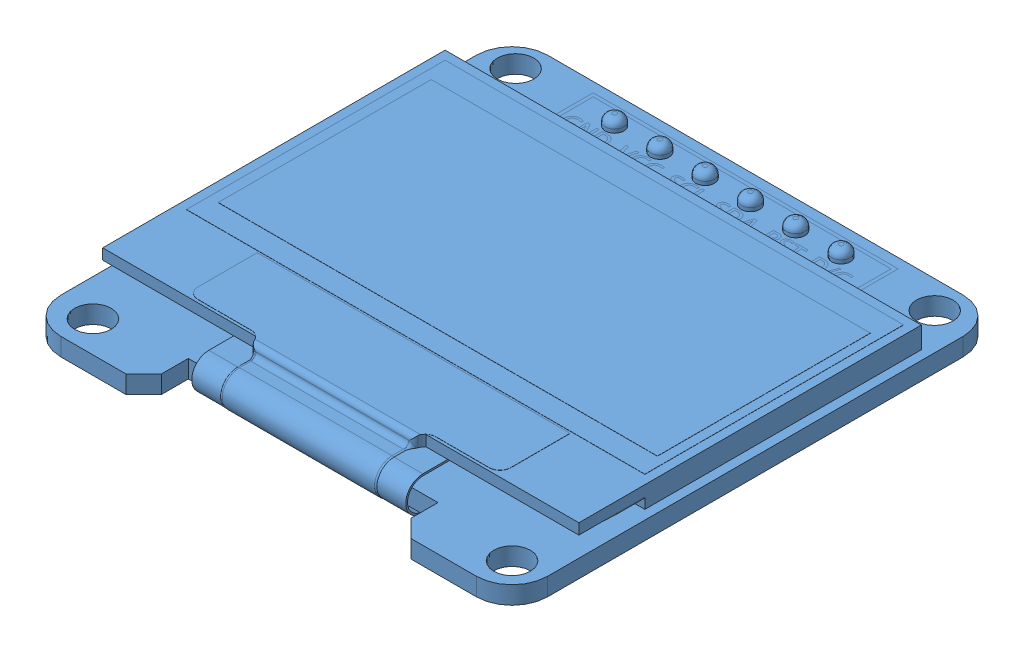
SolidWorks assembly display, configuration Default. Lengths in mm.
Overall size (27.3 3.37 27.3).
13 component instances, 3 part files, 0 mates.
Components (placement in the parent):
- oled_display-1: oled_display [Default] at (-42.7279 10.3551 15.964) size (27.3 2.57 27.3)
- Capacitor 0603_motor-1: Capacitor 0603_motor [Default] at (-47.8827 7.6343 13.4548) x (0 0 -1) z (1 0 0) size (1.6 0.86 0.86)
- Resistor 0603_motor-1: Resistor 0603_motor [Default] at (-45.8966 7.9986 13.4983) x (0 0 -1) z (1 0 0) size (1.6 0.51 0.86)
- Resistor 0603_motor-2: Resistor 0603_motor [Default] at (-43.8966 7.9986 13.4983) x (0 0 -1) z (1 0 0) size (1.6 0.51 0.86)
- Capacitor 0603_motor-2: Capacitor 0603_motor [Default] at (-49.8827 7.6343 13.4548) x (0 0 -1) z (1 0 0) size (1.6 0.86 0.86)
- Capacitor 0603_motor-3: Capacitor 0603_motor [Default] at (-51.8827 7.6343 13.4548) x (0 0 -1) z (1 0 0) size (1.6 0.86 0.86)
- Capacitor 0603_motor-4: Capacitor 0603_motor [Default] at (-53.8827 7.6343 13.4548) x (0 0 -1) z (1 0 0) size (1.6 0.86 0.86)
- Capacitor 0603_motor-5: Capacitor 0603_motor [Default] at (-41.8827 7.6343 13.4548) x (0 0 -1) z (1 0 0) size (1.6 0.86 0.86)
- Capacitor 0603_motor-6: Capacitor 0603_motor [Default] at (-37.8827 7.6343 13.4548) x (0 0 -1) z (1 0 0) size (1.6 0.86 0.86)
- Resistor 0603_motor-3: Resistor 0603_motor [Default] at (-39.8966 7.9986 13.4983) x (0 0 -1) z (1 0 0) size (1.6 0.51 0.86)
- Resistor 0603_motor-4: Resistor 0603_motor [Default] at (-35.8966 7.9986 13.4983) x (0 0 -1) z (1 0 0) size (1.6 0.51 0.86)
- Capacitor 0603_motor-7: Capacitor 0603_motor [Default] at (-33.8827 7.6343 13.4548) x (0 0 -1) z (1 0 0) size (1.6 0.86 0.86)
- Capacitor 0603_motor-8: Capacitor 0603_motor [Default] at (-31.8827 7.6343 13.4548) x (0 0 -1) z (1 0 0) size (1.6 0.86 0.86)
